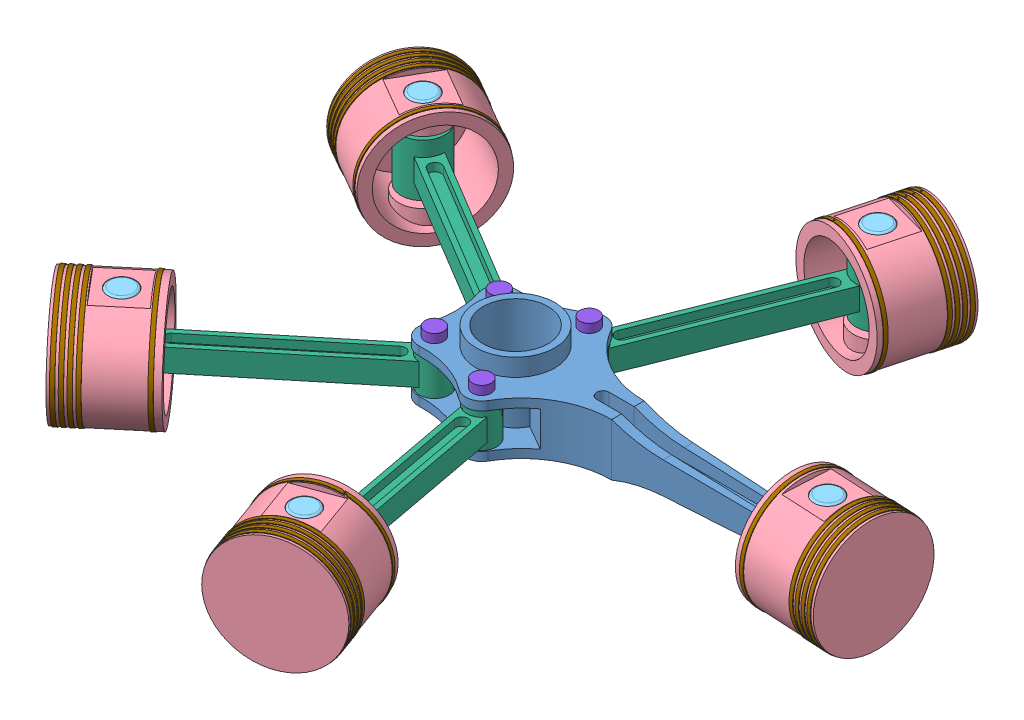
SolidWorks assembly Assem3, configuration Default. Lengths in mm.
Overall size (546.88 167.91 531.99).
63 component instances, 9 part files, 98 mates.
Components (placement in the parent):
- master rod-2: master rod [Default] at (125.0557 102.3994 245.0521) size (334.68 70 112)
- rod bush upper-1: rod bush upper [Default] at (375.0557 102.3994 245.0521) size (24 42 24)
- pinston pin-1: pinston pin [Default] at (375.0557 102.3994 245.0521) size (22 80 22)
- piston-1: piston [Default] at (372.7348 102.3994 244.9279) x (-0.053456 0 0.99857) z (-0.99857 0 -0.053456) size (92 92 66)
- piston plug-1: piston plug [Default] at (375.0557 142.3994 245.0521) size (22 15 22)
- piston plug-3: piston plug [Default] at (375.0557 62.3994 245.0521) x (-0.837169 0 -0.546944) z (-0.546944 0 0.837169) size (22 15 22)
- articulate rod-1: articulate rod [Default] at (141.0557 102.3994 202.0521) x (0.369376 0 -0.92928) z (0.92928 0 0.369376) size (207.5 42 35)
- articulate rod-2: articulate rod [Default] at (86.0557 102.3994 219.0521) x (-0.857743 0 -0.514079) z (0.514079 0 -0.857743) size (207.5 42 35)
- articulate rod-3: articulate rod [Default] at (86.0557 102.3994 271.0521) x (-0.772997 0 0.63441) z (-0.63441 0 -0.772997) size (207.5 42 35)
- articulate rod-4: articulate rod [Default] at (141.0557 102.3994 288.0521) x (0.184305 0 0.982869) z (-0.982869 0 0.184305) size (207.5 42 35)
- rod bush lower-1: rod bush lower [Default] at (86.0557 102.3994 271.0521) size (15 28 15)
- rod bush lower-2: rod bush lower [Default] at (86.0557 102.3994 219.0521) size (15 28 15)
- rod bush lower-3: rod bush lower [Default] at (141.0557 102.3994 202.0521) size (15 28 15)
- rod bush lower-4: rod bush lower [Default] at (141.0557 102.3994 288.0521) size (15 28 15)
- link pin-1: link pin [Default] at (86.0557 130.3994 271.0521) x (-0.837169 0 -0.546944) z (-0.546944 0 0.837169) size (15 50 15)
- link pin-2: link pin [Default] at (86.0557 130.3994 219.0521) x (-0.837169 0 -0.546944) z (-0.546944 0 0.837169) size (15 50 15)
- link pin-3: link pin [Default] at (141.0557 130.3994 202.0521) x (-0.837169 0 -0.546944) z (-0.546944 0 0.837169) size (15 50 15)
- link pin-4: link pin [Default] at (141.0557 130.3994 288.0521) x (-0.837169 0 -0.546944) z (-0.546944 0 0.837169) size (15 50 15)
- rod bush upper-2: rod bush upper [Default] at (-66.6225 102.3994 127.546) size (24 42 24)
- rod bush upper-3: rod bush upper [Default] at (206.8047 102.3994 36.6403) size (24 42 24)
- rod bush upper-4: rod bush upper [Default] at (-51.5378 102.3994 383.9771) size (24 42 24)
- rod bush upper-5: rod bush upper [Default] at (173.862 102.3994 463.0028) size (24 42 24)
- pinston pin-2: pinston pin [Default] at (-66.6225 102.3994 127.546) size (22 80 22)
- pinston pin-3: pinston pin [Default] at (206.8047 102.3994 36.6403) size (22 80 22)
- pinston pin-4: pinston pin [Default] at (-51.5378 102.3994 383.9771) size (22 80 22)
- pinston pin-5: pinston pin [Default] at (173.862 102.3994 463.0028) size (22 80 22)
- piston-2: piston [Default] at (206.2031 102.3994 38.8853) x (0.965926 0 0.258819) z (-0.258819 0 0.965926) size (92 92 66)
- piston-3: piston [Default] at (-64.6097 102.3994 128.7081) x (0.5 0 -0.866025) z (0.866025 0 0.5) size (92 92 66)
- piston-4: piston [Default] at (-49.7573 102.3994 382.4831) x (-0.642788 0 -0.766044) z (0.766044 0 -0.642788) size (92 92 66)
- piston-5: piston [Default] at (173.0671 102.3994 460.8188) x (-0.939693 0 0.34202) z (-0.34202 0 -0.939693) size (92 92 66)
- piston plug-4: piston plug [Default] at (-66.6225 142.3994 127.546) size (22 15 22)
- piston plug-5: piston plug [Default] at (173.862 142.3994 463.0028) size (22 15 22)
- piston plug-6: piston plug [Default] at (206.8047 142.3994 36.6403) size (22 15 22)
- piston plug-7: piston plug [Default] at (-51.5378 142.3994 383.9771) size (22 15 22)
- piston plug-8: piston plug [Default] at (173.862 62.3994 463.0028) x (-0.837169 0 -0.546944) z (-0.546944 0 0.837169) size (22 15 22)
- piston plug-9: piston plug [Default] at (-51.5378 62.3994 383.9771) x (-0.837169 0 -0.546944) z (-0.546944 0 0.837169) size (22 15 22)
- piston plug-10: piston plug [Default] at (-66.6225 62.3994 127.546) x (-0.837169 0 -0.546944) z (-0.546944 0 0.837169) size (22 15 22)
- piston plug-11: piston plug [Default] at (206.8047 62.3994 36.6403) x (-0.837169 0 -0.546944) z (-0.546944 0 0.837169) size (22 15 22)
- piston ring-1: piston ring [Default] at (-97.3664 102.3994 109.796) x (0.25 -0.866025 -0.433013) z (-0.433013 -0.5 0.75) size (93 3 93)
- piston ring-2: piston ring [Default] at (-93.0363 102.3994 112.296) x (0.25 -0.866025 -0.433013) z (-0.433013 -0.5 0.75) size (93 3 93)
- piston ring-3: piston ring [Default] at (-88.7062 102.3994 114.796) x (0.25 -0.866025 -0.433013) z (-0.433013 -0.5 0.75) size (93 3 93)
- piston ring-4: piston ring [Default] at (-84.3761 102.3994 117.296) x (0.25 -0.866025 -0.433013) z (-0.433013 -0.5 0.75) size (93 3 93)
- piston ring-5: piston ring [Default] at (-48.003 102.3994 138.296) x (0.25 -0.866025 -0.433013) z (-0.433013 -0.5 0.75) size (93 3 93)
- piston ring-6: piston ring [Default] at (215.9927 102.3994 2.3499) x (0.933013 0.258819 0.25) z (0.25 -0.965926 0.066987) size (93 3 93)
- piston ring-7: piston ring [Default] at (214.6987 102.3994 7.1796) x (0.933013 0.258819 0.25) z (0.25 -0.965926 0.066987) size (93 3 93)
- piston ring-8: piston ring [Default] at (213.4046 102.3994 12.0092) x (0.933013 0.258819 0.25) z (0.25 -0.965926 0.066987) size (93 3 93)
- piston ring-9: piston ring [Default] at (212.1105 102.3994 16.8388) x (0.933013 0.258819 0.25) z (0.25 -0.965926 0.066987) size (93 3 93)
- piston ring-10: piston ring [Default] at (201.2401 102.3994 57.4077) x (0.933013 0.258819 0.25) z (0.25 -0.965926 0.066987) size (93 3 93)
- piston ring-11: piston ring [Default] at (410.5049 102.3994 246.9498) x (0.002858 0.99857 -0.053379) z (-0.053379 0.053456 0.997142) size (93 3 93)
- piston ring-12: piston ring [Default] at (405.5121 102.3994 246.6825) x (0.002858 0.99857 -0.053379) z (-0.053379 0.053456 0.997142) size (93 3 93)
- piston ring-13: piston ring [Default] at (400.5192 102.3994 246.4152) x (0.002858 0.99857 -0.053379) z (-0.053379 0.053456 0.997142) size (93 3 93)
- piston ring-14: piston ring [Default] at (395.5264 102.3994 246.148) x (0.002858 0.99857 -0.053379) z (-0.053379 0.053456 0.997142) size (93 3 93)
- piston ring-15: piston ring [Default] at (353.5864 102.3994 243.9028) x (0.002858 0.99857 -0.053379) z (-0.053379 0.053456 0.997142) size (93 3 93)
- piston ring-16: piston ring [Default] at (186.0037 102.3994 496.3619) x (0.883022 0.34202 -0.321394) z (-0.321394 0.939693 0.116978) size (93 3 93)
- piston ring-17: piston ring [Default] at (184.2936 102.3994 491.6634) x (0.883022 0.34202 -0.321394) z (-0.321394 0.939693 0.116978) size (93 3 93)
- piston ring-18: piston ring [Default] at (182.5835 102.3994 486.965) x (0.883022 0.34202 -0.321394) z (-0.321394 0.939693 0.116978) size (93 3 93)
- piston ring-19: piston ring [Default] at (180.8734 102.3994 482.2665) x (0.883022 0.34202 -0.321394) z (-0.321394 0.939693 0.116978) size (93 3 93)
- piston ring-21: piston ring [Default] at (166.8506 102.3994 443.7391) x (0.883022 -0.34202 -0.321394) z (-0.321394 -0.939693 0.116978) size (93 3 93)
- piston ring-22: piston ring [Default] at (-78.7323 102.3994 406.7961) x (0.413176 -0.766044 0.492404) z (0.492404 0.642788 0.586824) size (93 3 93)
- piston ring-23: piston ring [Default] at (-74.9021 102.3994 403.5821) x (0.413176 -0.766044 0.492404) z (0.492404 0.642788 0.586824) size (93 3 93)
- piston ring-24: piston ring [Default] at (-71.0719 102.3994 400.3682) x (0.413176 -0.766044 0.492404) z (0.492404 0.642788 0.586824) size (93 3 93)
- piston ring-25: piston ring [Default] at (-67.2417 102.3994 397.1542) x (0.413176 -0.766044 0.492404) z (0.492404 0.642788 0.586824) size (93 3 93)
- piston ring-26: piston ring [Default] at (-35.8338 102.3994 370.7999) x (0.413176 -0.766044 0.492404) z (0.492404 0.642788 0.586824) size (93 3 93)
Mates (geometry in assembly coordinates):
- Concentric3: concentric aligned: cylinder of master rod-2 through (375.0557 123.3994 245.0521) axis (0 -1 0) radius 12; cylinder of rod bush upper-1 through (375.0557 123.3994 245.0521) axis (0 -1 0) radius 11
- Coincident1: coincident aligned: circle of master rod-2; plane of rod bush upper-1 through (375.0557 123.3994 245.0521) normal (0 1 0)
- Concentric4: concentric aligned: cylinder of rod bush upper-1 through (375.0557 123.3994 245.0521) axis (0 -1 0) radius 11; cylinder of pinston pin-1 through (375.0557 142.3994 245.0521) axis (0 -1 0) radius 11
- Coincident2: coincident aligned: plane of rod bush upper-1 through (375.0557 102.3994 245.0521) normal (0 1 0); plane of pinston pin-1 through (375.0557 102.3994 245.0521) normal (0 1 0)
- Concentric5: concentric anti-aligned: cylinder of pinston pin-1 through (375.0557 142.3994 245.0521) axis (0 -1 0) radius 11; cylinder of piston-1 through (375.0557 56.3994 245.0521) axis (0 1 0) radius 11
- Coincident3: coincident aligned: plane of pinston pin-1 through (375.0557 102.3994 245.0521) normal (0 1 0); plane of piston-1 through (372.7348 102.3994 244.9279) normal (0 1 0)
- Coincident7: coincident anti-aligned: plane of pinston pin-1 through (375.0557 142.3994 245.0521) normal (0 1 0); plane of piston plug-1 through (375.0557 142.3994 245.0521) normal (0 -1 0)
- Concentric7: concentric aligned: circle of pinston pin-1; circle of piston plug-1
- Coincident9: coincident anti-aligned: plane of pinston pin-1 through (375.0557 62.3994 245.0521) normal (0 -1 0); plane of piston plug-3 through (375.0557 62.3994 245.0521) normal (0 1 0)
- Concentric8: concentric anti-aligned: circle of pinston pin-1; circle of piston plug-3
- Concentric9: concentric aligned: cylinder of master rod-2 through (141.0557 123.3994 202.0521) axis (0 -1 0) radius 5; cylinder of articulate rod-1 through (141.0557 116.3994 202.0521) axis (0 -1 0) radius 7.5
- Coincident10: coincident anti-aligned: plane of master rod-2 through (89.9376 116.3994 134.1408) normal (0 -1 0); plane of articulate rod-1 through (141.0557 116.3994 202.0521) normal (0 1 0)
- Concentric10: concentric aligned: cylinder of master rod-2 through (86.0557 123.3994 219.0521) axis (0 -1 0) radius 5; cylinder of articulate rod-2 through (86.0557 116.3994 219.0521) axis (0 -1 0) radius 7.5
- Coincident11: coincident anti-aligned: plane of master rod-2 through (89.9376 116.3994 134.1408) normal (0 -1 0); plane of articulate rod-2 through (86.0557 116.3994 219.0521) normal (0 1 0)
- Concentric11: concentric aligned: cylinder of master rod-2 through (86.0557 123.3994 271.0521) axis (0 -1 0) radius 5; cylinder of articulate rod-3 through (86.0557 116.3994 271.0521) axis (0 -1 0) radius 7.5
- Coincident12: coincident anti-aligned: plane of master rod-2 through (89.9376 116.3994 134.1408) normal (0 -1 0); plane of articulate rod-3 through (86.0557 116.3994 271.0521) normal (0 1 0)
- Concentric12: concentric aligned: cylinder of master rod-2 through (141.0557 123.3994 288.0521) axis (0 -1 0) radius 5; cylinder of articulate rod-4 through (141.0557 116.3994 288.0521) axis (0 -1 0) radius 7.5
- Coincident13: coincident anti-aligned: plane of master rod-2 through (89.9376 116.3994 134.1408) normal (0 -1 0); plane of articulate rod-4 through (141.0557 116.3994 288.0521) normal (0 1 0)
- Concentric13: concentric aligned: cylinder of master rod-2 through (86.0557 123.3994 271.0521) axis (0 -1 0) radius 5; cylinder of rod bush lower-1 through (86.0557 116.3994 271.0521) axis (0 -1 0) radius 6
- Coincident14: coincident anti-aligned: plane of master rod-2 through (89.9376 116.3994 134.1408) normal (0 -1 0); plane of rod bush lower-1 through (86.0557 116.3994 271.0521) normal (0 1 0)
- Concentric14: concentric aligned: cylinder of master rod-2 through (86.0557 123.3994 219.0521) axis (0 -1 0) radius 5; cylinder of rod bush lower-2 through (86.0557 116.3994 219.0521) axis (0 -1 0) radius 6
- Coincident16: coincident anti-aligned: plane of master rod-2 through (89.9376 116.3994 134.1408) normal (0 -1 0); plane of rod bush lower-2 through (86.0557 116.3994 219.0521) normal (0 1 0)
- Coincident17: coincident anti-aligned: plane of master rod-2 through (89.9376 116.3994 134.1408) normal (0 -1 0); plane of rod bush lower-3 through (141.0557 116.3994 202.0521) normal (0 1 0)
- Concentric16: concentric aligned: circle of master rod-2; circle of rod bush lower-3
- Coincident18: coincident anti-aligned: plane of master rod-2 through (89.9376 116.3994 134.1408) normal (0 -1 0); plane of rod bush lower-4 through (141.0557 116.3994 288.0521) normal (0 1 0)
- Concentric17: concentric aligned: circle of master rod-2; circle of rod bush lower-4
- Coincident19: coincident anti-aligned: plane of master rod-2 through (89.9376 123.3994 134.1408) normal (0 1 0); plane of link pin-1 through (86.0557 123.3994 271.0521) normal (0 -1 0)
- Concentric18: concentric anti-aligned: circle of master rod-2; circle of link pin-1
- Coincident20: coincident anti-aligned: plane of master rod-2 through (89.9376 123.3994 134.1408) normal (0 1 0); plane of link pin-2 through (86.0557 123.3994 219.0521) normal (0 -1 0)
- Concentric19: concentric anti-aligned: circle of master rod-2; circle of link pin-2
- Coincident21: coincident anti-aligned: plane of master rod-2 through (89.9376 123.3994 134.1408) normal (0 1 0); plane of link pin-3 through (141.0557 123.3994 202.0521) normal (0 -1 0)
- Concentric20: concentric anti-aligned: circle of master rod-2; circle of link pin-3
- Coincident22: coincident anti-aligned: plane of master rod-2 through (89.9376 123.3994 134.1408) normal (0 1 0); plane of link pin-4 through (141.0557 123.3994 288.0521) normal (0 -1 0)
- Concentric21: concentric anti-aligned: circle of master rod-2; circle of link pin-4
- Concentric22: concentric aligned: cylinder of articulate rod-2 through (-66.6225 123.3994 127.546) axis (0 -1 0) radius 12; cylinder of rod bush upper-2 through (-66.6225 123.3994 127.546) axis (0 -1 0) radius 11
- Coincident23: coincident aligned: plane of articulate rod-2 through (-66.6225 123.3994 127.546) normal (0 1 0); plane of rod bush upper-2 through (-66.6225 123.3994 127.546) normal (0 1 0)
- Concentric23: concentric aligned: cylinder of articulate rod-1 through (206.8047 123.3994 36.6403) axis (0 -1 0) radius 12; cylinder of rod bush upper-3 through (206.8047 123.3994 36.6403) axis (0 -1 0) radius 11
- Coincident24: coincident aligned: plane of articulate rod-1 through (206.8047 123.3994 36.6403) normal (0 1 0); plane of rod bush upper-3 through (206.8047 123.3994 36.6403) normal (0 1 0)
- Concentric24: concentric aligned: cylinder of articulate rod-3 through (-51.5378 123.3994 383.9771) axis (0 -1 0) radius 12; cylinder of rod bush upper-4 through (-51.5378 123.3994 383.9771) axis (0 -1 0) radius 11
- Coincident25: coincident aligned: plane of articulate rod-3 through (-51.5378 123.3994 383.9771) normal (0 1 0); plane of rod bush upper-4 through (-51.5378 123.3994 383.9771) normal (0 1 0)
- Concentric25: concentric aligned: cylinder of articulate rod-4 through (173.862 123.3994 463.0028) axis (0 -1 0) radius 12; cylinder of rod bush upper-5 through (173.862 123.3994 463.0028) axis (0 -1 0) radius 11
- Coincident26: coincident aligned: plane of articulate rod-4 through (173.862 123.3994 463.0028) normal (0 1 0); plane of rod bush upper-5 through (173.862 123.3994 463.0028) normal (0 1 0)
- Concentric26: concentric aligned: cylinder of rod bush upper-2 through (-66.6225 123.3994 127.546) axis (0 -1 0) radius 11; cylinder of pinston pin-2 through (-66.6225 142.3994 127.546) axis (0 -1 0) radius 5.5
- Coincident27: coincident aligned: plane of rod bush upper-5 through (173.862 102.3994 463.0028) normal (0 1 0); plane of pinston pin-2 through (-66.6225 102.3994 127.546) normal (0 1 0)
- Concentric27: concentric aligned: cylinder of rod bush upper-3 through (206.8047 123.3994 36.6403) axis (0 -1 0) radius 11; cylinder of pinston pin-3 through (206.8047 142.3994 36.6403) axis (0 -1 0) radius 5.5
- Coincident28: coincident aligned: plane of rod bush upper-3 through (206.8047 102.3994 36.6403) normal (0 1 0); plane of pinston pin-3 through (206.8047 102.3994 36.6403) normal (0 1 0)
- Concentric28: concentric aligned: cylinder of rod bush upper-4 through (-51.5378 123.3994 383.9771) axis (0 -1 0) radius 11; cylinder of pinston pin-4 through (-51.5378 142.3994 383.9771) axis (0 -1 0) radius 5.5
- Coincident29: coincident aligned: plane of rod bush upper-4 through (-51.5378 102.3994 383.9771) normal (0 1 0); plane of pinston pin-4 through (-51.5378 102.3994 383.9771) normal (0 1 0)
- Concentric29: concentric aligned: cylinder of rod bush upper-5 through (173.862 123.3994 463.0028) axis (0 -1 0) radius 11; cylinder of pinston pin-5 through (173.862 142.3994 463.0028) axis (0 -1 0) radius 5.5
- Coincident30: coincident aligned: plane of rod bush upper-5 through (173.862 102.3994 463.0028) normal (0 1 0); plane of pinston pin-5 through (173.862 102.3994 463.0028) normal (0 1 0)
- Concentric30: concentric anti-aligned: cylinder of pinston pin-3 through (206.8047 142.3994 36.6403) axis (0 -1 0) radius 11; cylinder of piston-2 through (206.8047 56.3994 36.6403) axis (0 1 0) radius 11
- Coincident31: coincident aligned: plane of pinston pin-3 through (206.8047 102.3994 36.6403) normal (0 1 0); plane of piston-2 through (206.2031 102.3994 38.8853) normal (0 1 0)
- Concentric31: concentric anti-aligned: cylinder of pinston pin-2 through (-66.6225 142.3994 127.546) axis (0 -1 0) radius 11; cylinder of piston-3 through (-66.6225 56.3994 127.546) axis (0 1 0) radius 11
- Coincident32: coincident aligned: plane of pinston pin-2 through (-66.6225 102.3994 127.546) normal (0 1 0); plane of piston-3 through (-64.6097 102.3994 128.7081) normal (0 1 0)
- Concentric32: concentric anti-aligned: cylinder of pinston pin-4 through (-51.5378 142.3994 383.9771) axis (0 -1 0) radius 11; cylinder of piston-4 through (-51.5378 56.3994 383.9771) axis (0 1 0) radius 11
- Coincident33: coincident aligned: plane of pinston pin-4 through (-51.5378 102.3994 383.9771) normal (0 1 0); plane of piston-4 through (-49.7573 102.3994 382.4831) normal (0 1 0)
- Concentric33: concentric anti-aligned: cylinder of pinston pin-5 through (173.862 142.3994 463.0028) axis (0 -1 0) radius 11; cylinder of piston-5 through (173.862 56.3994 463.0028) axis (0 1 0) radius 11
- Coincident34: coincident aligned: plane of pinston pin-5 through (173.862 102.3994 463.0028) normal (0 1 0); plane of piston-5 through (173.0671 102.3994 460.8188) normal (0 1 0)
- Parallel3: parallel anti-aligned: line of piston-5 through (180.0035 102.3994 479.8764) axis (-0.34202 0 -0.939693)
- Parallel4: parallel anti-aligned: line of piston-4 through (-65.2932 102.3994 395.5193) axis (0.766044 0 -0.642788)
- Parallel5: parallel anti-aligned: line of piston-3 through (-82.1733 102.3994 118.5678) axis (0.866025 0 0.5)
- Parallel6: parallel anti-aligned: line of piston-2 through (211.4522 102.3994 19.2956) axis (-0.258819 0 0.965926)
- Coincident39: coincident anti-aligned: plane of pinston pin-2 through (-66.6225 142.3994 127.546) normal (0 1 0); plane of piston plug-4 through (-66.6225 142.3994 127.546) normal (0 -1 0)
- Concentric34: concentric aligned: circle of pinston pin-2; circle of piston plug-4
- Coincident40: coincident anti-aligned: plane of pinston pin-4 through (-51.5378 142.3994 383.9771) normal (0 1 0); plane of piston plug-7 through (-51.5378 142.3994 383.9771) normal (0 -1 0)
- Concentric35: concentric aligned: circle of pinston pin-4; circle of piston plug-7
- Coincident41: coincident anti-aligned: plane of pinston pin-5 through (173.862 142.3994 463.0028) normal (0 1 0); plane of piston plug-5 through (173.862 142.3994 463.0028) normal (0 -1 0)
- Concentric36: concentric aligned: circle of pinston pin-5; circle of piston plug-5
- Coincident42: coincident anti-aligned: plane of pinston pin-3 through (206.8047 142.3994 36.6403) normal (0 1 0); plane of piston plug-6 through (206.8047 142.3994 36.6403) normal (0 -1 0)
- Concentric37: concentric aligned: circle of pinston pin-3; circle of piston plug-6
- Coincident43: coincident anti-aligned: plane of pinston pin-5 through (173.862 62.3994 463.0028) normal (0 -1 0); plane of piston plug-8 through (173.862 62.3994 463.0028) normal (0 1 0)
- Concentric38: concentric anti-aligned: circle of pinston pin-5; circle of piston plug-8
- Coincident44: coincident anti-aligned: plane of pinston pin-4 through (-51.5378 62.3994 383.9771) normal (0 -1 0); plane of piston plug-9 through (-51.5378 62.3994 383.9771) normal (0 1 0)
- Concentric39: concentric anti-aligned: circle of pinston pin-4; circle of piston plug-9
- Coincident45: coincident anti-aligned: plane of pinston pin-2 through (-66.6225 62.3994 127.546) normal (0 -1 0); plane of piston plug-10 through (-66.6225 62.3994 127.546) normal (0 1 0)
- Concentric40: concentric anti-aligned: circle of pinston pin-2; circle of piston plug-10
- Coincident46: coincident anti-aligned: plane of pinston pin-3 through (206.8047 62.3994 36.6403) normal (0 -1 0); plane of piston plug-11 through (206.8047 62.3994 36.6403) normal (0 1 0)
- Concentric41: concentric anti-aligned: circle of pinston pin-3; circle of piston plug-11
- Concentric42: concentric anti-aligned: cylinder of piston-3 through (-64.6097 102.3994 128.7081) axis (0.866025 0 0.5) radius 46; cylinder of piston ring-1 through (-96.0674 102.3994 110.546) axis (-0.866025 0 -0.5) radius 42
- Coincident47: coincident anti-aligned: plane of piston-3 through (-75.6655 102.3994 69.2089) normal (0.866025 0 0.5); plane of piston ring-1 through (-98.6655 102.3994 109.046) normal (-0.866025 0 -0.5)
- Concentric44: concentric anti-aligned: cylinder of piston-3 through (-64.6097 102.3994 128.7081) axis (0.866025 0 0.5) radius 46; cylinder of piston ring-5 through (-46.704 102.3994 139.046) axis (-0.866025 0 -0.5) radius 42
- Coincident50: coincident anti-aligned: plane of piston-3 through (-26.302 102.3994 97.7089) normal (0.866025 0 0.5); plane of piston ring-5 through (-49.302 102.3994 137.546) normal (-0.866025 0 -0.5)
- Concentric45: concentric anti-aligned: cylinder of piston-2 through (206.2031 102.3994 38.8853) axis (-0.258819 0 0.965926) radius 46; cylinder of piston ring-6 through (215.6045 102.3994 3.7988) axis (0.258819 0 -0.965926) radius 42
- Coincident51: coincident anti-aligned: plane of piston-2 through (260.8136 102.3994 12.8067) normal (-0.258819 0 0.965926); plane of piston ring-6 through (216.381 102.3994 0.901) normal (0.258819 0 -0.965926)
- Coincident52: coincident anti-aligned: plane of piston-2 through (246.0609 102.3994 67.8645) normal (-0.258819 0 0.965926); plane of piston ring-10 through (201.6283 102.3994 55.9588) normal (0.258819 0 -0.965926)
- Concentric47: concentric anti-aligned: cylinder of piston-2 through (206.2031 102.3994 38.8853) axis (-0.258819 0 0.965926) radius 46; cylinder of piston ring-10 through (200.8518 102.3994 58.8566) axis (0.258819 0 -0.965926) radius 46.5
- Concentric48: concentric anti-aligned: cylinder of piston-1 through (372.7348 102.3994 244.9279) axis (-0.99857 0 -0.053456) radius 46; cylinder of piston ring-11 through (409.0071 102.3994 246.8696) axis (0.99857 0 0.053456) radius 42
- Coincident53: coincident anti-aligned: plane of piston-1 through (406.7619 102.3994 288.8096) normal (0.99857 0 0.053456); plane of piston ring-11 through (409.0071 102.3994 246.8696) normal (-0.99857 0 -0.053456)
- Concentric49: concentric anti-aligned: cylinder of piston-1 through (372.7348 102.3994 244.9279) axis (-0.99857 0 -0.053456) radius 46; cylinder of piston ring-15 through (352.0886 102.3994 243.8226) axis (0.99857 0 0.053456) radius 42
- Coincident54: coincident anti-aligned: plane of piston-1 through (352.6253 102.3994 289.9172) normal (-0.99857 0 -0.053456); plane of piston ring-15 through (355.0843 102.3994 243.983) normal (0.99857 0 0.053456)
- Concentric50: concentric anti-aligned: cylinder of piston-5 through (173.0671 102.3994 460.8188) axis (-0.34202 0 -0.939693) radius 46; cylinder of piston ring-16 through (185.4907 102.3994 494.9524) axis (0.34202 0 0.939693) radius 42
- Coincident55: coincident anti-aligned: plane of piston ring-16 through (186.5168 102.3994 497.7714) normal (0.34202 0 0.939693); plane of piston-5 through (143.2909 102.3994 513.5044) normal (-0.34202 0 -0.939693)
- Coincident57: coincident anti-aligned: plane of piston-5 through (126.8705 102.3994 456.6944) normal (0.34202 0 0.939693); plane of piston ring-21 through (166.3376 102.3994 442.3296) normal (-0.34202 0 -0.939693)
- Concentric52: concentric anti-aligned: circle of piston-5; circle of piston ring-21
- Concentric53: concentric anti-aligned: cylinder of piston-4 through (-49.7573 102.3994 382.4831) axis (0.766044 0 -0.642788) radius 46; cylinder of piston ring-22 through (-77.5833 102.3994 405.8319) axis (-0.766044 0 0.642788) radius 42
- Coincident58: coincident anti-aligned: plane of piston-4 through (-104.5803 102.3994 373.658) normal (-0.766044 0 0.642788); plane of piston ring-22 through (-77.5833 102.3994 405.8319) normal (0.766044 0 -0.642788)
- Concentric54: concentric anti-aligned: cylinder of piston-4 through (-49.7573 102.3994 382.4831) axis (0.766044 0 -0.642788) radius 46; cylinder of piston ring-26 through (-34.6848 102.3994 369.8358) axis (-0.766044 0 0.642788) radius 42
- Coincident59: coincident anti-aligned: plane of piston-4 through (-61.6819 102.3994 337.6619) normal (-0.766044 0 0.642788); plane of piston ring-26 through (-34.6848 102.3994 369.8358) normal (0.766044 0 -0.642788)
